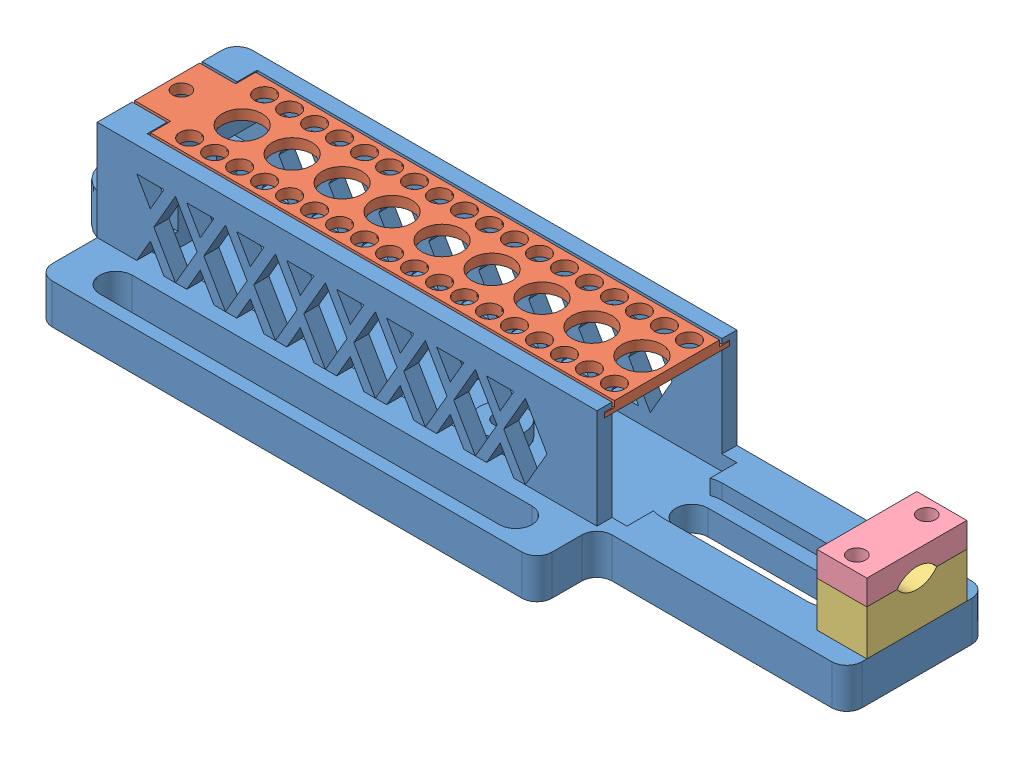
SolidWorks assembly temp_housing, configuration Standard. Lengths in mm.
Overall size (162.5 28 40).
4 component instances, 4 part files, 6 mates.
Components (placement in the parent):
- temp_base-1: temp_base [Standard] at (-10.0383 -10.1908 0) size (162.5 28 40)
- temp_lid-1: temp_lid [Standard] at (39.9617 43.1788 22.1559) x (-1 0 0) z (0 0 -1) size (100 2 25)
- hum_cable-clamp1-1: hum_cable-clamp1 [Standard] at (89.9617 -2.1908 -16) x (0 0 1) z (-1 0 0) size (20 9 10)
- hum_cable-clamp2-1: hum_cable-clamp2 [Standard] at (79.9617 11.8092 -16) x (0 0 1) z (1 0 0) size (20 5 10)
Mates (geometry in assembly coordinates):
- Deckungsgleich1: coincident anti-aligned: circle of temp_base-1; circle of temp_lid-1
- Parallel1: parallel anti-aligned: line of temp_base-1 through (39.9617 17.8092 5) axis (-1 0 0); line of temp_lid-1 through (-54.0383 16.6092 6.5) axis (1 0 0)
- Deckungsgleich2: coincident aligned: circle of temp_base-1; circle of hum_cable-clamp1-1
- Konzentrisch1: concentric aligned: cylinder of temp_base-1 through (84.9617 -10.1909 -13) axis (0 1 0) radius 1.75; cylinder of hum_cable-clamp1-1 through (84.9617 -2.1908 -13) axis (0 1 0) radius 1.75
- Deckungsgleich3: coincident anti-aligned: circle of hum_cable-clamp1-1; circle of hum_cable-clamp2-1
- Konzentrisch2: concentric anti-aligned: cylinder of hum_cable-clamp1-1 through (84.9617 -2.1908 -13) axis (0 1 0) radius 1.75; cylinder of hum_cable-clamp2-1 through (84.9617 11.8092 -13) axis (0 -1 0) radius 1.75
